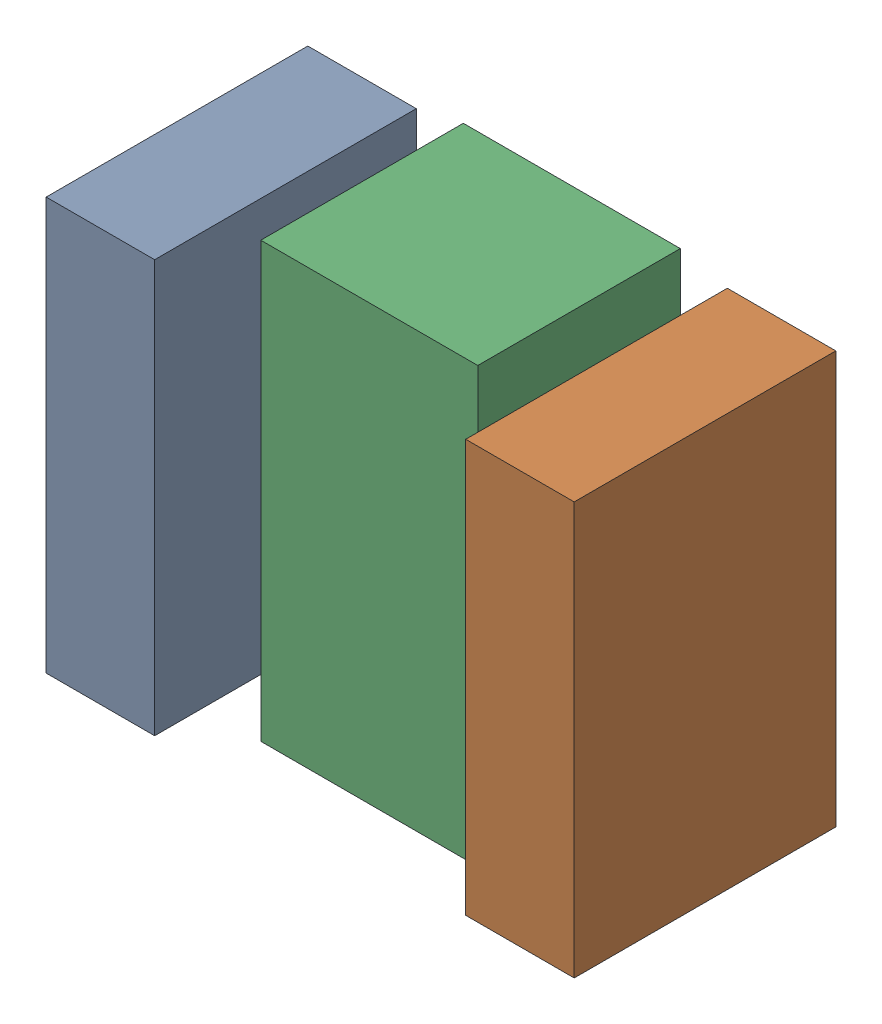
SolidWorks assembly C7_Motor_1Kanaloa_v2.0.0_Motor, configuration Default. Lengths in mm.
Overall size (3.65 3 1.81).
6 component instances, 2 part files, 0 mates.
Components (placement in the parent):
- 334788400-1: 334788400 [Default] at (102.198 56.642 0) size (0.75 2.85 1.81)
  - Extruded_5-1: Extruded_5 [Default] at origin size (0.75 2.85 1.81)
- 334788400-2: 334788400 [Default] at (105.098 56.642 0) size (0.75 2.85 1.81)
  - Extruded_5-1: Extruded_5 [Default] at origin size (0.75 2.85 1.81)
- 334788656-1: 334788656 [Default] at (103.648 56.642 0) size (1.5 3 1.4)
  - Extruded_1-1: Extruded_1 [Default] at origin size (1.5 3 1.4)
